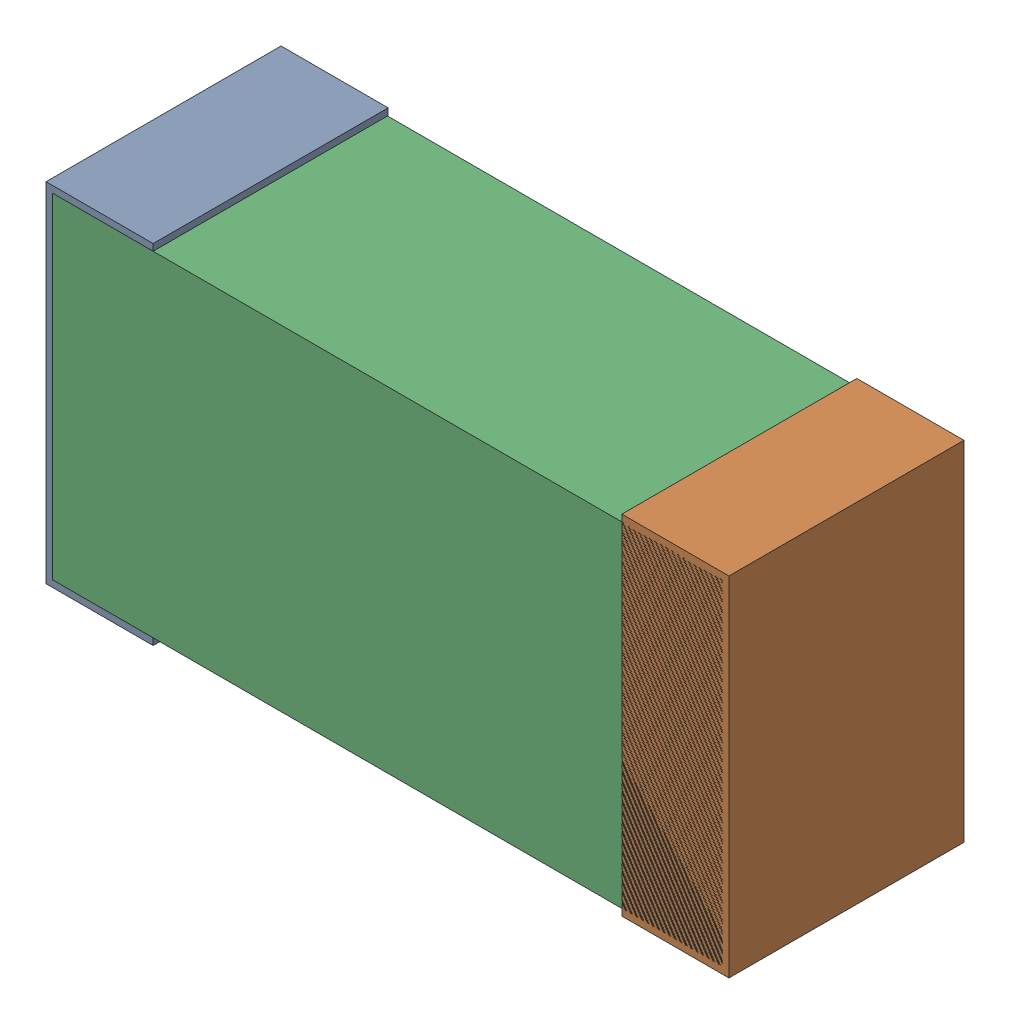
SolidWorks assembly C18, configuration Default. Lengths in mm.
Overall size (1.02 0.52 0.35).
6 component instances, 2 part files, 0 mates.
Components (placement in the parent):
- 870940480-1: 870940480 [Default] at (53.722 33.3988 -1.9516) size (0.16 0.52 0.35)
  - Extruded-1: Extruded [Default] at origin size (0.16 0.52 0.35)
- 870940480-2: 870940480 [Default] at (54.582 33.3988 -1.9516) size (0.16 0.52 0.35)
  - Extruded-1: Extruded [Default] at origin size (0.16 0.52 0.35)
- 870940640-1: 870940640 [Default] at (54.152 33.3988 -1.9506) size (1 0.5 0.35)
  - Extruded_2-1: Extruded_2 [Default] at origin size (1 0.5 0.35)
